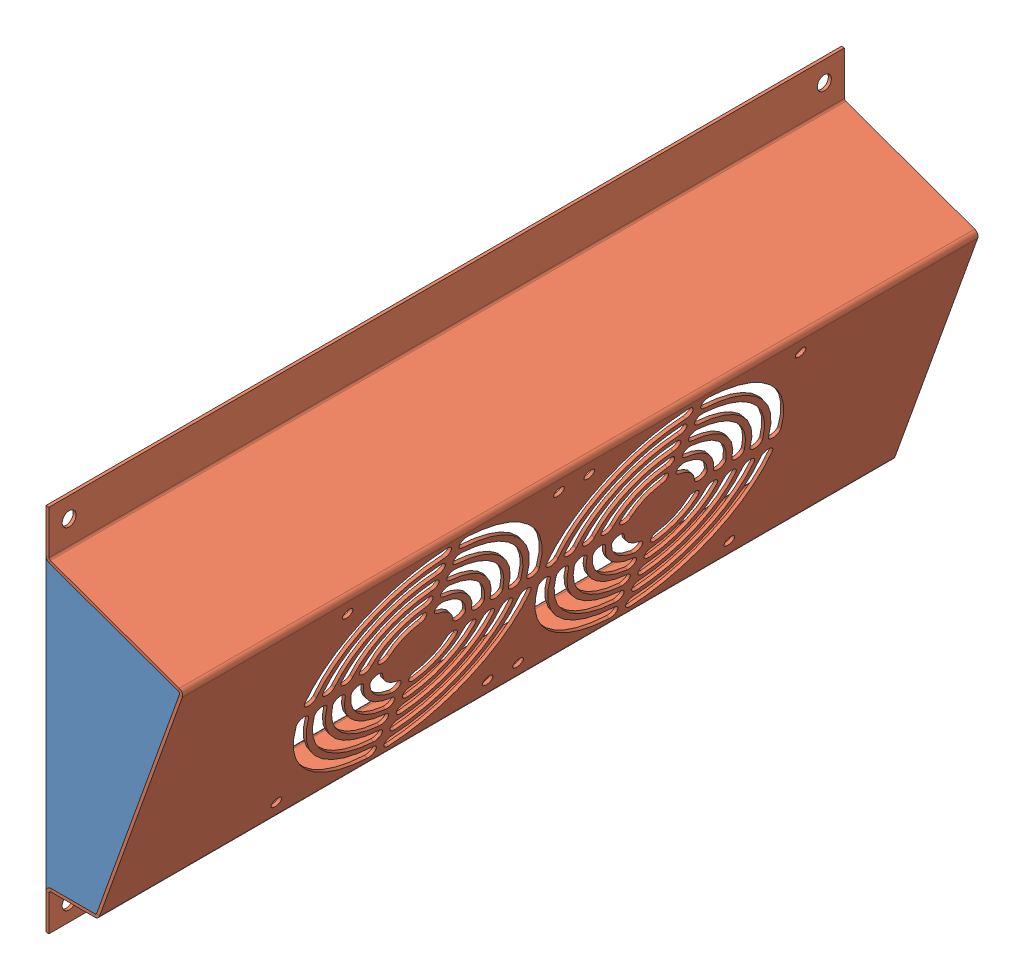
SolidWorks assembly Сборка6, configuration По умолчанию. Lengths in mm.
Overall size (67.81 183.46 395).
3 component instances, 2 part files, 6 mates.
Components (placement in the parent):
- Боковина вент-блока-1: Боковина вент-блока [По умолчанию] at origin size (66.31 144.3 1.5)
- Крышка вент-блока-1: Крышка вент-блока [По умолчанию] at origin size (67.81 183.46 395)
- Боковина вент-блока-2: Боковина вент-блока [По умолчанию] at (0 0 -393.5) size (66.31 144.3 1.5)
Mates (geometry in assembly coordinates):
- Совпадение1: coincident: plane of Боковина вент-блока-1 through (4 3.3463 0) normal (0 0 1); plane of Крышка вент-блока-1 through (69.1678 -23.7388 0) normal (0 0 1)
- Совпадение2: coincident: plane of Боковина вент-блока-1 through (67.1521 -21.9537 -1.5) normal (0.337523 0.941317 0); plane of Крышка вент-блока-1 through (68.0934 -22.2912 -590.5894) normal (-0.337523 -0.941317 0)
- Совпадение3: coincident: plane of Боковина вент-блока-1 through (26.678 -137.7944 -1.5) normal (0.941317 -0.337523 0); plane of Крышка вент-блока-1 through (26.4405 -138.4569 -590.5894) normal (-0.941317 0.337523 0)
- Совпадение4: coincident: plane of Крышка вент-блока-1 through (68.0934 -22.2912 -590.5894) normal (-0.337523 -0.941317 0); plane of Боковина вент-блока-2 through (67.1521 -21.9537 -395) normal (0.337523 0.941317 0)
- Совпадение5: coincident: plane of Крышка вент-блока-1 through (26.4405 -138.4569 -590.5894) normal (-0.941317 0.337523 0); plane of Боковина вент-блока-2 through (26.678 -137.7944 -395) normal (0.941317 -0.337523 0)
- Совпадение6: coincident: plane of Крышка вент-блока-1 through (26.4405 -138.4569 -395) normal (0 0 -1); plane of Боковина вент-блока-2 through (4 3.3463 -395) normal (0 0 -1)
